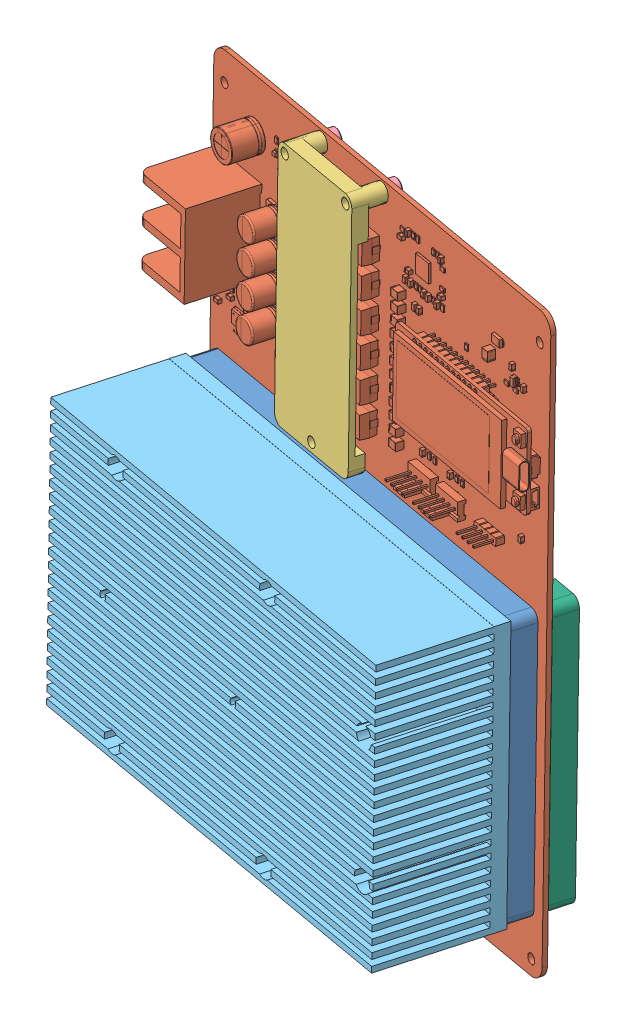
SolidWorks assembly Assemblage NerdEKO V1.0 Heatsink ASICs, configuration Défaut. Lengths in mm.
Overall size (165.02 202.95 95.63).
10 component instances, 6 part files, 23 mates.
Components (placement in the parent):
- Heatsink Nerd EKO - base ASICs V1.0-1: Heatsink Nerd EKO - base ASICs V1.0 [Défaut] at (-14.0995 -43.4943 63.7939) x (-0.975933 -0.048959 -0.212502) z (0.214709 -0.045333 -0.975625) size (150 90 8)
- EKO_Miner NerdEKO V1.0-2: EKO_Miner NerdEKO V1.0 [Défaut] at (-202.4609 158.9415 2.3768) x (0.975933 0.048959 0.212502) z (-0.214709 0.045333 0.975625) size (155.59 194.55 26.81)
- Heatsink Nerd EKO - PSU V1.0-1: Heatsink Nerd EKO - PSU V1.0 [Défaut] at (-88.7346 56.3769 44.8805) x (-0.975933 -0.048959 -0.212502) z (0.214709 -0.045333 -0.975625) size (34 83 10.8)
- CHC3 M3x6mm-1: CHC3 M3x6mm [M3X6mm] at (-91.4064 135.3536 24.8381) x (-0.915283 -0.35792 -0.184799) z (0.214709 -0.045333 -0.975625) size (5.5 5.5 9.19)
- CHC3 M3x6mm-2: CHC3 M3x6mm [M3X6mm] at (-118.7326 133.9827 18.888) x (-0.915283 -0.35792 -0.184799) z (0.214709 -0.045333 -0.975625) size (5.5 5.5 9.19)
- CHC3 M3x6mm-3: CHC3 M3x6mm [M3X6mm] at (-102.1333 57.8397 26.0791) x (-0.915283 -0.35792 -0.184799) z (0.214709 -0.045333 -0.975625) size (5.5 5.5 9.19)
- CHC3 M3x6mm-4: CHC3 M3x6mm [M3X6mm] at (-143.9981 -38.5955 14.6843) x (-0.915283 -0.35792 -0.184799) z (0.214709 -0.045333 -0.975625) size (5.5 5.5 9.19)
- CHC3 M3x6mm-5: CHC3 M3x6mm [M3X6mm] at (-26.2236 52.286 36.3805) x (-0.915283 -0.35792 -0.184799) z (0.214709 -0.045333 -0.975625) size (5.5 5.5 9.19)
- Heatsink Nerd EKO - part B ASICs V1.0-1: Heatsink Nerd EKO - part B ASICs V1.0 [Défaut] at (-23.0395 -31.6715 102.2764) x (-0.975933 -0.04896 -0.212502) z (0.214709 -0.045333 -0.975625) size (150 90 40)
- Heatsink Nerd EKO - bottom ASICs V1.0-1: Heatsink Nerd EKO - bottom ASICs V1.0 [Défaut] at (-161.9838 58.4225 13.9055) x (0.975933 0.048959 0.212502) z (0.214709 -0.045333 -0.975625) size (150 90 10)
Mates (geometry in assembly coordinates):
- Coaxiale1: concentric aligned: cylinder of Heatsink Nerd EKO - ASICs V1.0-1 through (-149.7729 46.75 21.5426) axis (0.214709 -0.045333 -0.975625) radius 1.7; cylinder of EKO_Miner NerdEKO V1.0-2 through (-149.2694 46.6437 19.2548) axis (0.214709 -0.045333 -0.975625) radius 1.6
- Coaxiale2: concentric aligned: cylinder of Heatsink Nerd EKO - ASICs V1.0-1 through (-25.5159 -31.9896 52.547) axis (0.214709 -0.045333 -0.975625) radius 1.7; cylinder of EKO_Miner NerdEKO V1.0-2 through (-25.0124 -32.0959 50.2591) axis (0.214709 -0.045333 -0.975625) radius 1.6
- Coïncidente1: coincident anti-aligned: plane of Heatsink Nerd EKO - ASICs V1.0-1 through (-15.7757 -31.0012 54.6446) normal (0.214709 -0.045333 -0.975625); plane of EKO_Miner NerdEKO V1.0-2 through (-27.5644 -11.139 51.1273) normal (-0.214709 0.045333 0.975625)
- Coaxiale3: concentric aligned: cylinder of EKO_Miner NerdEKO V1.0-2 through (-102.7678 57.9737 28.9621) axis (0.214709 -0.045333 -0.975625) radius 1.6; cylinder of Heatsink Nerd EKO - PSU V1.0-1 through (-103.121 58.0483 30.567) axis (0.214709 -0.045333 -0.975625) radius 1.7
- Coaxiale6: concentric aligned: cylinder of EKO_Miner NerdEKO V1.0-2 through (-92.0409 135.4875 27.7211) axis (0.214709 -0.045333 -0.975625) radius 1.6; cylinder of Heatsink Nerd EKO - PSU V1.0-1 through (-92.3941 135.5621 29.326) axis (0.214709 -0.045333 -0.975625) radius 1.7
- Coïncidente2: coincident anti-aligned: plane of EKO_Miner NerdEKO V1.0-2 through (-202.8045 159.0141 3.9378) normal (-0.214709 0.045333 0.975625); plane of Heatsink Nerd EKO - PSU V1.0-1 through (-92.3941 135.5621 29.326) normal (0.214709 -0.045333 -0.975625)
- Coaxiale7: concentric aligned: cylinder of EKO_Miner NerdEKO V1.0-2 through (-119.367 134.1167 21.771) axis (0.214709 -0.045333 -0.975625) radius 1.6; cylinder of CHC3 M3x6mm-2 through (-118.7326 133.9827 18.888) axis (0.214709 -0.045333 -0.975625) radius 1.5
- Coaxiale8: concentric aligned: cylinder of EKO_Miner NerdEKO V1.0-2 through (-92.0409 135.4875 27.7211) axis (0.214709 -0.045333 -0.975625) radius 1.6; cylinder of CHC3 M3x6mm-1 through (-91.4064 135.3536 24.8381) axis (0.214709 -0.045333 -0.975625) radius 1.5
- Coaxiale9: concentric aligned: cylinder of EKO_Miner NerdEKO V1.0-2 through (-102.7678 57.9737 28.9621) axis (0.214709 -0.045333 -0.975625) radius 1.6; cylinder of CHC3 M3x6mm-3 through (-102.1333 57.8397 26.0791) axis (0.214709 -0.045333 -0.975625) radius 1.5
- Coïncidente3: coincident anti-aligned: plane of EKO_Miner NerdEKO V1.0-2 through (-202.4609 158.9415 2.3768) normal (0.214709 -0.045333 -0.975625); plane of CHC3 M3x6mm-2 through (-120.2407 136.483 21.5149) normal (-0.214709 0.045333 0.975625)
- Coïncidente4: coincident anti-aligned: plane of EKO_Miner NerdEKO V1.0-2 through (-202.4609 158.9415 2.3768) normal (0.214709 -0.045333 -0.975625); plane of CHC3 M3x6mm-1 through (-92.9145 137.8538 27.465) normal (-0.214709 0.045333 0.975625)
- Coïncidente5: coincident anti-aligned: plane of EKO_Miner NerdEKO V1.0-2 through (-202.4609 158.9415 2.3768) normal (0.214709 -0.045333 -0.975625); plane of CHC3 M3x6mm-3 through (-103.6414 60.34 28.706) normal (-0.214709 0.045333 0.975625)
- Coaxiale10: concentric aligned: cylinder of EKO_Miner NerdEKO V1.0-2 through (-146.0282 -38.1668 23.9089) axis (0.214709 -0.045333 -0.975625) radius 1.6; cylinder of CHC3 M3x6mm-4 through (-143.9981 -38.5955 14.6843) axis (0.214709 -0.045333 -0.975625) radius 1.5
- Distance1: distance = 6.5 mm anti-aligned: plane of EKO_Miner NerdEKO V1.0-2 through (-202.4609 158.9415 2.3768) normal (0.214709 -0.045333 -0.975625); plane of CHC3 M3x6mm-4 through (-145.5062 -36.0952 17.3112) normal (-0.214709 0.045333 0.975625)
- Coaxiale11: concentric aligned: cylinder of EKO_Miner NerdEKO V1.0-2 through (-28.2537 52.7146 45.605) axis (0.214709 -0.045333 -0.975625) radius 1.6; cylinder of CHC3 M3x6mm-5 through (-26.2236 52.286 36.3805) axis (0.214709 -0.045333 -0.975625) radius 1.5
- Distance2: distance = 6.5 mm anti-aligned: plane of EKO_Miner NerdEKO V1.0-2 through (-202.4609 158.9415 2.3768) normal (0.214709 -0.045333 -0.975625); plane of CHC3 M3x6mm-5 through (-27.7317 54.7863 39.0074) normal (-0.214709 0.045333 0.975625)
- Coaxiale18: concentric anti-aligned: cylinder of Heatsink Nerd EKO - base ASICs V1.0-1 through (-20.2544 -9.5636 60.8627) axis (0.214709 -0.045333 -0.975625) radius 1.6; cylinder of Heatsink Nerd EKO - part B ASICs V1.0-1 through (-20.2544 -9.5636 60.8627) axis (-0.214709 0.045333 0.975625) radius 1.3
- Coaxiale21: concentric anti-aligned: cylinder of Heatsink Nerd EKO - base ASICs V1.0-1 through (-134.8044 45.4506 33.097) axis (0.214709 -0.045333 -0.975625) radius 1.6; cylinder of Heatsink Nerd EKO - part B ASICs V1.0-1 through (-134.8044 45.4506 33.097) axis (-0.214709 0.045333 0.975625) radius 1.3
- Coaxiale22: concentric anti-aligned: cylinder of Heatsink Nerd EKO - base ASICs V1.0-1 through (-131.7538 -34.3711 37.4774) axis (0.214709 -0.045333 -0.975625) radius 1.6; cylinder of Heatsink Nerd EKO - part B ASICs V1.0-1 through (-131.7538 -34.3711 37.4774) axis (-0.214709 0.045333 0.975625) radius 1.3
- Coïncidente6: coincident anti-aligned: plane of Heatsink Nerd EKO - base ASICs V1.0-1 through (-17.4933 -30.6385 62.4496) normal (-0.214709 0.045333 0.975625); plane of Heatsink Nerd EKO - part B ASICs V1.0-1 through (-14.4511 -33.4848 63.2514) normal (0.214709 -0.045333 -0.975625)
- Coaxiale23: concentric aligned: cylinder of EKO_Miner NerdEKO V1.0-2 through (-147.6488 4.2384 21.5818) axis (0.214709 -0.045333 -0.975625) radius 1.6; cylinder of Heatsink Nerd EKO - bottom ASICs V1.0-1 through (-147.229 4.1498 19.6745) axis (0.214709 -0.045333 -0.975625) radius 1.6
- Coaxiale24: concentric aligned: cylinder of EKO_Miner NerdEKO V1.0-2 through (-26.6331 10.3093 47.9321) axis (0.214709 -0.045333 -0.975625) radius 1.6; cylinder of Heatsink Nerd EKO - bottom ASICs V1.0-1 through (-26.2133 10.2207 46.0247) axis (0.214709 -0.045333 -0.975625) radius 1.6
- Coïncidente7: coincident anti-aligned: plane of EKO_Miner NerdEKO V1.0-2 through (-202.4609 158.9415 2.3768) normal (0.214709 -0.045333 -0.975625); plane of Heatsink Nerd EKO - bottom ASICs V1.0-1 through (-25.0221 -32.0939 50.303) normal (-0.214709 0.045333 0.975625)
